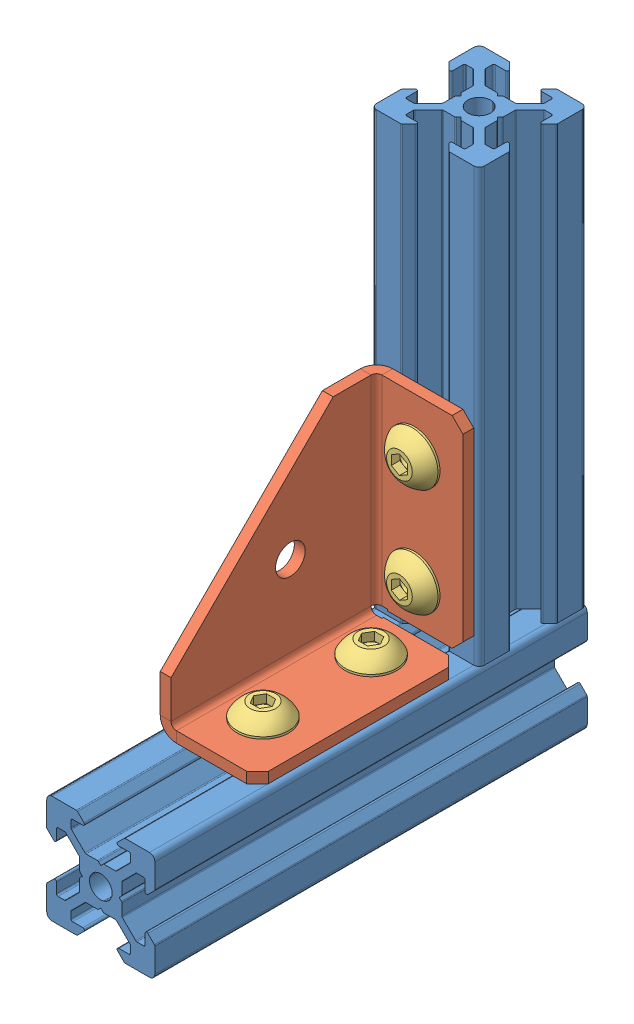
SolidWorks assembly Уголок 20 серия 1х4 40х40х18х2 с перемычкой СБ, configuration По умолчанию. Lengths in mm.
Overall size (20 100 80).
7 component instances, 3 part files, 14 mates.
Components (placement in the parent):
- 2020100-1: 2020100 [По умолчанию] at origin size (20 20 80)
- 2020100-2: 2020100 [По умолчанию] at (0 10 10) x (1 0 0) z (0 1 0) size (20 20 80)
- Уголок 20 серия 1х4 40х40х18х2 с перемычкой-1: Уголок 20 серия 1х4 40х40х18х2 с перемычкой [По умолчанию] at (-9 10 20) size (18 40 40)
- socket button head screw_iso-5: socket button head screw_iso [ISO 7380 - M5 x 10 - 10N] at (0 40 24.75) x (0 0 -1) z (1 0 0) size (12.75 9.5 9.5)
- socket button head screw_iso-6: socket button head screw_iso [ISO 7380 - M5 x 10 - 10N] at (0 20 24.75) x (0 0 -1) z (1 0 0) size (12.75 9.5 9.5)
- socket button head screw_iso-7: socket button head screw_iso [ISO 7380 - M5 x 10 - 10N] at (0 14.75 30) x (0 -1 0) z (0 0 1) size (12.75 9.5 9.5)
- socket button head screw_iso-8: socket button head screw_iso [ISO 7380 - M5 x 10 - 10N] at (0 14.75 50) x (0 -1 0) z (0 0 1) size (12.75 9.5 9.5)
Mates (geometry in assembly coordinates):
- Совпадение1: coincident aligned: plane of 2020100-1 through (10 10 80) normal (1 0 0); plane of 2020100-2 through (10 90 20) normal (1 0 0)
- Совпадение2: coincident anti-aligned: plane of 2020100-1 through (10 10 80) normal (0 1 0); plane of 2020100-2 through (0 10 10) normal (0 -1 0)
- Совпадение3: coincident anti-aligned: plane of 2020100-1 through (-10 10 80) normal (0 1 0); plane of Уголок 20 серия 1х4 40х40х18х2 с перемычкой-1 through (9 10 60) normal (0 -1 0)
- Совпадение4: coincident anti-aligned: plane of 2020100-2 through (-10 90 20) normal (0 0 1); plane of Уголок 20 серия 1х4 40х40х18х2 с перемычкой-1 through (9 10 20) normal (0 0 -1)
- Совпадение5: coincident aligned: plane of 2020100-1 through (0 0 0) normal (0 0 -1); plane of 2020100-2 through (-10 90 0) normal (0 0 -1)
- Расстояние1: distance = 1 mm aligned: plane of 2020100-1 through (10 10 80) normal (1 0 0); plane of Уголок 20 серия 1х4 40х40х18х2 с перемычкой-1 through (9 10 60) normal (1 0 0)
- Концентричный1: concentric aligned: cylinder of Уголок 20 серия 1х4 40х40х18х2 с перемычкой-1 through (0 40 22) axis (0 0 1) radius 2.75; cylinder of socket button head screw_iso-5 through (0 40 24.75) axis (0 0 1) radius 4.75
- Совпадение6: coincident anti-aligned: plane of Уголок 20 серия 1х4 40х40х18х2 с перемычкой-1 through (9 10 22) normal (0 0 1); plane of socket button head screw_iso-5 through (0 42.5 22) normal (0 0 -1)
- Концентричный2: concentric aligned: cylinder of Уголок 20 серия 1х4 40х40х18х2 с перемычкой-1 through (0 20 22) axis (0 0 1) radius 2.75; cylinder of socket button head screw_iso-6 through (0 20 24.75) axis (0 0 1) radius 4.75
- Совпадение7: coincident anti-aligned: plane of Уголок 20 серия 1х4 40х40х18х2 с перемычкой-1 through (9 10 22) normal (0 0 1); plane of socket button head screw_iso-6 through (0 22.5 22) normal (0 0 -1)
- Концентричный3: concentric aligned: cylinder of Уголок 20 серия 1х4 40х40х18х2 с перемычкой-1 through (0 12 30) axis (0 1 0) radius 2.75; cylinder of socket button head screw_iso-7 through (0 14.75 30) axis (0 1 0) radius 4.75
- Совпадение8: coincident anti-aligned: plane of Уголок 20 серия 1х4 40х40х18х2 с перемычкой-1 through (9 12 60) normal (0 1 0); plane of socket button head screw_iso-7 through (2.5 12 30) normal (0 -1 0)
- Концентричный4: concentric aligned: cylinder of Уголок 20 серия 1х4 40х40х18х2 с перемычкой-1 through (0 12 50) axis (0 1 0) radius 2.75; cylinder of socket button head screw_iso-8 through (0 14.75 50) axis (0 1 0) radius 4.75
- Совпадение9: coincident anti-aligned: plane of Уголок 20 серия 1х4 40х40х18х2 с перемычкой-1 through (9 12 60) normal (0 1 0); plane of socket button head screw_iso-8 through (2.5 12 50) normal (0 -1 0)
